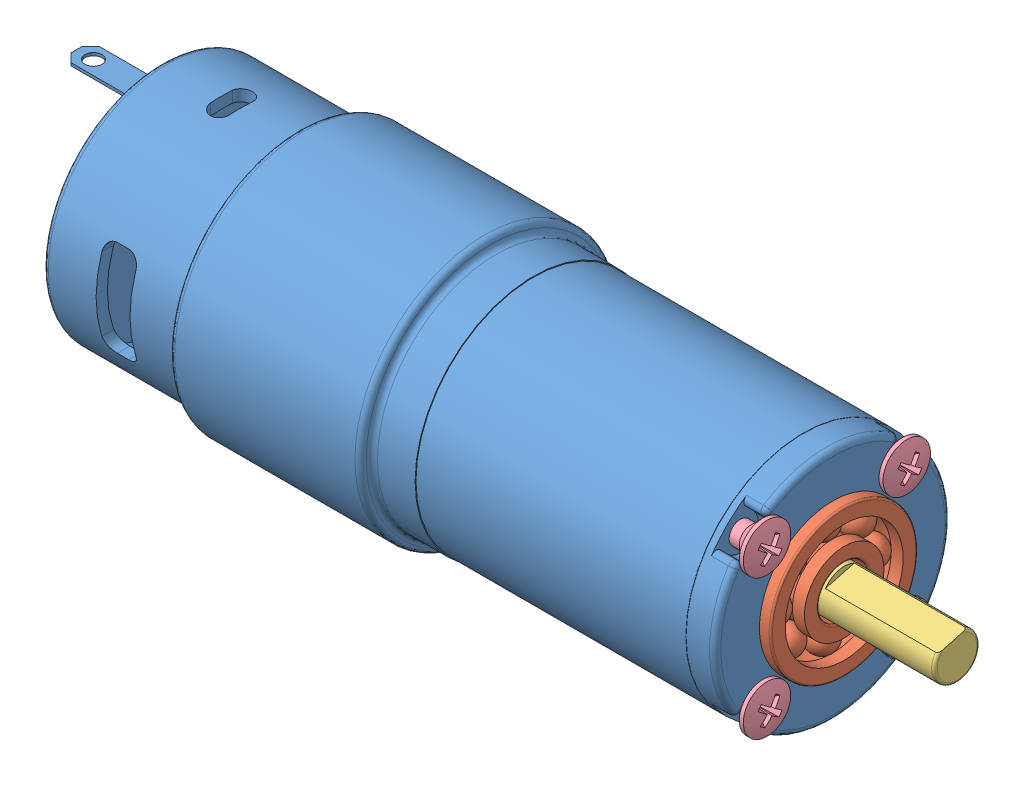
SolidWorks assembly MEGA TORQUE PLANETARY DC GEARED MOTOR 250W 300RPM 18VDC, configuration Varsayılan. Lengths in mm.
Overall size (156.02 46 46).
7 component instances, 4 part files, 12 mates.
Components (placement in the parent):
- MEGA TORQUE PLANETARY DC GEARED MOTOR 250W 300RPM 18VDC-1: MEGA TORQUE PLANETARY DC GEARED MOTOR 250W 300RPM 18VDC [Varsayılan] at (-51.9559 -9.2971 0) size (133.96 46 46)
- instrument ball bearing_68_am-1: instrument ball bearing_68_am [AFBMA 12.1.4.1 - 0090-26 - 8,DE,NC,8_68] at (-2.4559 -9.2971 0) size (8 26 26)
- 8x147mm motor mili-1: 8x147mm motor mili [Varsayılan] at (21.5441 -9.2971 0) x (-1 0 0) z (0 0.255684 -0.96676) size (147.06 8 8)
- oval head_am-2: oval head_am [B18.6.7M - M4 x 0.7 x 16 Type I Cross Recessed OHMS --16N] at (1.0389 3.0772 -12.3744) x (-1 0 0) z (0 -0.587871 -0.808955) size (16.97 8.4 8.4)
- oval head_am-6: oval head_am [B18.6.7M - M4 x 0.7 x 16 Type I Cross Recessed OHMS --16N] at (1.0389 -21.6715 -12.3744) x (-1 0 0) z (0 -0.587871 -0.808955) size (16.97 8.4 8.4)
- oval head_am-7: oval head_am [B18.6.7M - M4 x 0.7 x 16 Type I Cross Recessed OHMS --16N] at (1.0389 3.0772 12.3744) x (-1 0 0) z (0 -0.587871 -0.808955) size (16.97 8.4 8.4)
- oval head_am-8: oval head_am [B18.6.7M - M4 x 0.7 x 16 Type I Cross Recessed OHMS --16N] at (1.0389 -21.6715 12.3744) x (-1 0 0) z (0 -0.587871 -0.808955) size (16.97 8.4 8.4)
Mates (geometry in assembly coordinates):
- Concentric1: concentric aligned: cylinder of MEGA TORQUE PLANETARY DC GEARED MOTOR 250W 300RPM 18VDC-1 through (-3.4559 -9.2971 0) axis (1 0 0) radius 13; cylinder of instrument ball bearing_68_am-1 through (-23.0934 -9.2971 0) axis (1 0 0) radius 4.5
- Distance1: distance = 2 mm aligned: plane of instrument ball bearing_68_am-1 through (1.5441 3.4029 0) normal (1 0 0); plane of MEGA TORQUE PLANETARY DC GEARED MOTOR 250W 300RPM 18VDC-1 through (-0.4559 11.5529 0) normal (1 0 0)
- Concentric2: concentric aligned: cylinder of instrument ball bearing_68_am-1 through (-23.0934 -9.2971 0) axis (1 0 0) radius 4.5; cylinder of 8x147mm motor mili-1 through (-125.4559 -9.2971 0) axis (1 0 0) radius 4
- Coincident2: coincident aligned: plane of MEGA TORQUE PLANETARY DC GEARED MOTOR 250W 300RPM 18VDC-1 through (-125.4559 -5.2971 0) normal (-1 0 0); plane of 8x147mm motor mili-1 through (-125.4559 -9.2971 0) normal (-1 0 0)
- Concentric7: concentric anti-aligned: cylinder of MEGA TORQUE PLANETARY DC GEARED MOTOR 250W 300RPM 18VDC-1 through (-18.4559 3.0772 -12.3744) axis (1 0 0) radius 2; cone of oval head_am-2 through (-2.6559 3.0772 -12.3744) axis (-1 0 0)
- Coincident7: coincident aligned: plane of oval head_am-6 through (-15.9559 -21.6715 -12.3744) normal (-1 0 0); plane of oval head_am-8 through (-15.9559 -21.6715 12.3744) normal (-1 0 0)
- Coincident8: coincident aligned: plane of oval head_am-6 through (-15.9559 -21.6715 -12.3744) normal (-1 0 0); plane of oval head_am-7 through (-15.9559 3.0772 12.3744) normal (-1 0 0)
- Concentric11: concentric aligned: cylinder of MEGA TORQUE PLANETARY DC GEARED MOTOR 250W 300RPM 18VDC-1 through (-18.4559 3.0772 12.3744) axis (1 0 0) radius 2; cylinder of oval head_am-7 through (16.9139 3.0772 12.3744) axis (1 0 0) radius 2
- Concentric12: concentric aligned: cylinder of MEGA TORQUE PLANETARY DC GEARED MOTOR 250W 300RPM 18VDC-1 through (-18.4559 -21.6715 12.3744) axis (1 0 0) radius 2; cylinder of oval head_am-8 through (16.9139 -21.6715 12.3744) axis (1 0 0) radius 2
- Concentric13: concentric aligned: cylinder of MEGA TORQUE PLANETARY DC GEARED MOTOR 250W 300RPM 18VDC-1 through (-18.4559 -21.6715 -12.3744) axis (1 0 0) radius 2; cylinder of oval head_am-6 through (16.9139 -21.6715 -12.3744) axis (1 0 0) radius 2
- Coincident9: coincident aligned: plane of oval head_am-2 through (-1.9511 3.4299 -12.3185) normal (1 0 0); plane of oval head_am-6 through (-1.9511 -21.3188 -12.3185) normal (1 0 0)
- Coincident10: coincident aligned: plane of MEGA TORQUE PLANETARY DC GEARED MOTOR 250W 300RPM 18VDC-1 through (-0.4559 11.5529 0) normal (1 0 0); circle of oval head_am-8
